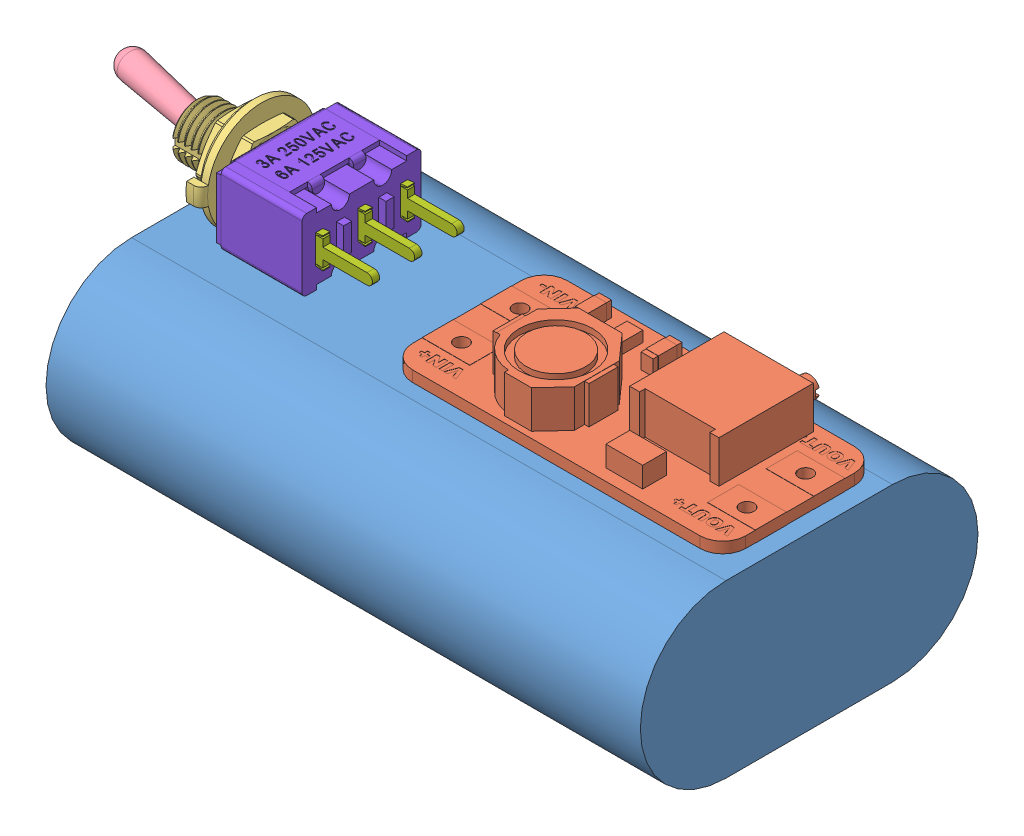
SolidWorks assembly bateria, configuration Default. Lengths in mm.
Overall size (79.03 35.23 37.5).
25 component instances, 18 part files, 9 mates.
Components (placement in the parent):
- bateria-1: bateria [Valor predeterminado] at (23.6654 23.8156 58.3925) size (66 19 37.5)
- MT3608-Module.stp-1: MT3608-Module.stp [Default] at (41.8628 45.0348 63.9384) x (-1 0 0) z (0 1 0) size (37.01 17.71 6.5)
- MTS-1xx-A2-blue-OFF.step-1: MTS-1xx-A2-blue-OFF.step [Default] at (7.7654 47.7656 58.3925) x (0 -1 0) z (-1 0 0) size (12 13.4 35.63)
  - eBom-prt0.step-1: eBom-prt0.step [Default] at (0 0 10.3) x (1 0 0) z (0 1 0) size (12 9.99 12.8)
  - Handle.step-1: Handle.step [Default] at (0 0 19.1) x (-1 0 0) z (0 -1 0) size (3.8 17.38 5.93)
  - eBom-prt2.step-1: eBom-prt2.step [Default] at (0 0 4.4) x (-1 0 0) z (0 -1 0) size (3.55 1.36 10.22)
  - L.step-1: L.step [Default] at (0 -0.1062 17.6994) x (1 0 0) z (0 0.978148 0.207912) size (3.55 20.58 3.55)
  - eBom-prt4.step-1: eBom-prt4.step [Default] at (0 0 4.4) size (3.7 10.2 9.9)
  - Housing.step-1: Housing.step [Default] at (0 0 10.3) x (1 0 0) z (0 1 0) size (7.9 10.3 13.2)
- Lipo Charger - With Load Protection.stp-1: Lipo Charger - With Load Protection.stp [Default] at (3.7972 22.8156 58.3925) x (1 0 0) z (0 -1 0) size (26.91 17.09 4.28)
  - bOARD.stp-1: bOARD.stp [Default] at origin size (26.26 17.09 1.68)
  - 0603 Capacitor.stp-1: 0603 Capacitor.stp [Default] at (1.3663 2.3089 1.5723) x (0 -1 0) z (0 0 1) size (1.6 0.84 0.84)
  - 0603 Resistor.stp-1: 0603 Resistor.stp [Default] at (-2.0999 -6.1665 1.5723) size (1.6 0.85 0.56)
  - 0603 Resistor.stp-2: 0603 Resistor.stp [Default] at (-6.7314 4.6411 1.5723) size (1.6 0.85 0.56)
  - 0805 Capacitor.stp-1: 0805 Capacitor.stp [Default] at (3.543 2.3802 1.5723) x (0 -1 0) z (0 0 1) size (2.01 1.27 0.84)
  - 0603 Capacitor.stp-2: 0603 Capacitor.stp [Default] at (-6.6654 -6.2522 1.5723) size (1.6 0.84 0.84)
  - SOIC-8-150.stp-1: SOIC-8-150.stp [Default] at (-3.5116 0.0462 2.4718) x (-1 0 0) z (0 1 0) size (5 1.75 6.2)
  - LED - 0805 - Blue.stp-1: LED - 0805 - Blue.stp [Default] at (-6.7354 7.0496 1.5448) size (2 1.25 0.83)
  - LED - 0805 - Red.stp-1: LED - 0805 - Red.stp [Default] at (-0.6772 7.1069 1.5448) x (-1 0 0) z (0 0 1) size (2 1.25 0.83)
  - 0603 Resistor.stp-3: 0603 Resistor.stp [Default] at (-2.2661 4.8273 1.5723) size (1.6 0.85 0.56)
  - USB - Micro.stp-1: USB - Micro.stp [Default] at (-7.8617 -2.8878 1.1998) x (0 -1 0) z (-1 0 0) size (7.92 3.01 5.67)
  - tsop8.stp-1: tsop8.stp [Default] at (7.7511 -2.5035 1.4748) x (0 1 0) z (0 0 1) size (6.4 3.1 1.2)
  - sot-23-6-2.stp-1: sot-23-6-2.stp [Default] at (7.8055 3.8715 1.5748) x (0 1 0) z (0 0 1) size (2.43 2.79 1.09)
  - 0603 Resistor.stp-4: 0603 Resistor.stp [Default] at (4.561 -4.8365 1.5723) x (0 1 0) z (0 0 1) size (1.6 0.85 0.56)
  - 0603 Resistor.stp-5: 0603 Resistor.stp [Default] at (3.7053 6.1769 1.5723) x (0 -1 0) z (0 0 1) size (1.6 0.85 0.56)
Mates (geometry in assembly coordinates):
- Distance1: distance = 1 mm anti-aligned: plane of MT3608-Module.stp-1 through (37.1615 43.8156 58.3925) normal (0 -1 0); plane of bateria-1 through (23.6654 42.8156 58.3925) normal (0 1 0)
- Symmetric1: symmetric aligned: plane of bateria-1 through (23.6654 23.8156 58.3925) normal (0 0 1); plane of MT3608-Module.stp-1 through (55.6654 43.8156 49.8073) normal (0 0 -1); plane of MT3608-Module.stp-1 through (18.6576 43.8156 66.9777) normal (0 0 1)
- Distance2: distance = 1 mm aligned: plane of MT3608-Module.stp-1 through (55.6654 43.8156 66.9777) normal (1 0 0); plane of bateria-1 through (56.6654 42.8156 39.6425) normal (1 0 0)
- Distance3: distance = 1 mm anti-aligned: plane of MTS-1xx-A2-blue-OFF.step-1/Housing.step-1 through (-5.7945 43.8156 58.3925) normal (0 -1 0); plane of bateria-1 through (23.6654 42.8156 58.3925) normal (0 1 0)
- Distance4: distance = 2 mm aligned: plane of MTS-1xx-A2-blue-OFF.step-1/eBom-prt0.step-1 through (-11.3346 47.7656 58.3925) normal (-1 0 0); plane of bateria-1 through (-9.3346 42.8156 39.6425) normal (-1 0 0)
- Symmetric2: symmetric aligned: plane of bateria-1 through (23.6654 23.8156 58.3925) normal (0 0 1); plane of MTS-1xx-A2-blue-OFF.step-1/Housing.step-1 through (6.4654 44.3156 64.9925) normal (0 0 1); plane of MTS-1xx-A2-blue-OFF.step-1/Housing.step-1 through (6.4654 51.2156 51.7925) normal (0 0 -1)
- Distance5: distance = 1 mm anti-aligned: plane of Lipo Charger - With Load Protection.stp-1/bOARD.stp-1 through (3.7972 22.8156 58.3925) normal (0 1 0); plane of bateria-1 through (23.6654 23.8156 58.3925) normal (0 -1 0)
- Coincident7: coincident aligned: plane of bateria-1 through (-9.3346 42.8156 39.6425) normal (-1 0 0); plane of Lipo Charger - With Load Protection.stp-1/bOARD.stp-1 through (-9.3346 21.2408 49.8454) normal (-1 0 0)
- Symmetric3: symmetric aligned: plane of bateria-1 through (23.6654 23.8156 58.3925) normal (0 0 1); plane of Lipo Charger - With Load Protection.stp-1/bOARD.stp-1 through (16.929 21.2408 49.8454) normal (0 0 -1); plane of Lipo Charger - With Load Protection.stp-1/bOARD.stp-1 through (-9.3346 21.2408 66.9396) normal (0 0 1)
